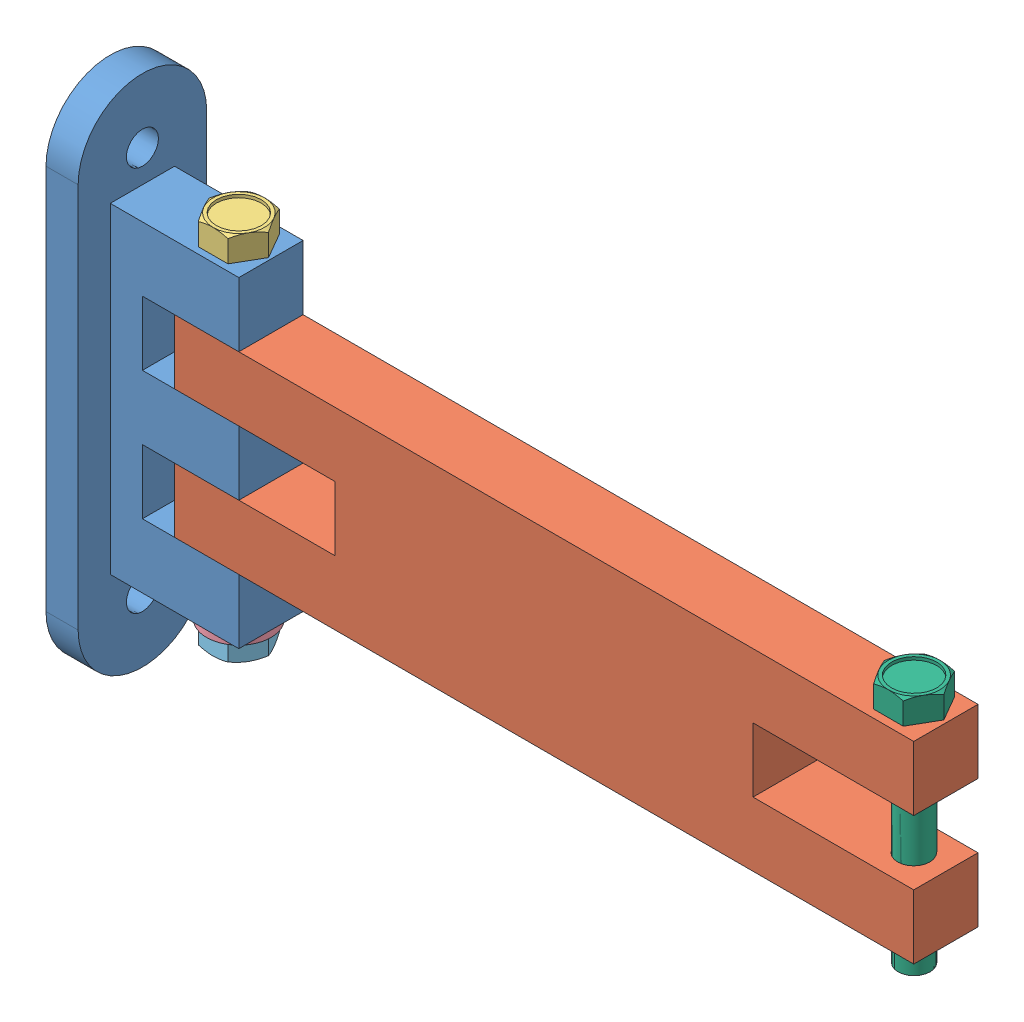
SolidWorks assembly TV Bracket, configuration Default. Lengths in mm.
Overall size (260 160 40).
6 component instances, 6 part files, 10 mates.
Components (placement in the parent):
- Wall Anchor-1: Wall Anchor [Default] at origin size (50 160 40)
- Link Arm-1: Link Arm [Default] at (135 0 0) size (230 60 20)
- M10 X 110 Bolt-1: M10 X 110 Bolt [B18.6.7M - M10 x 1.5 x 70 Indented HHMS --38N] at (30 57.5 0) x (0 -1 0) z (-0.866025 0 0.5) size (117.5 18.48 16)
- M10 Washer-1: M10 Washer [Default] at (30 -52 0) x (0 1 0) z (0 0 1) size (2 20 20)
- M10 Nut-1: M10 Nut [B18.2.4.1M - Hex nut, Style 1,  M10 x 1.5, with 16mm WAF --D-N] at (30 -52 0) x (0.866025 0 -0.5) z (0 1 0) size (16 18.48 6)
- M10 X 70 Bolt-1: M10 X 70 Bolt [B18.6.7M - M10 x 1.5 x 70 Indented HHMS --38N] at (239.7664 37.6092 -0.3551) x (0 -1 0) z (0 0 1) size (77.5 18.48 16)
Mates (geometry in assembly coordinates):
- Concentric1: concentric aligned: cylinder of Wall Anchor-1 through (30 -80 0) axis (0 1 0) radius 5; cylinder of Link Arm-1 through (30 -30 0) axis (0 1 0) radius 5
- Coincident1: coincident anti-aligned: plane of Wall Anchor-1 through (40 30 10) normal (0 -1 0); plane of Link Arm-1 through (250 30 10) normal (0 1 0)
- Concentric2: concentric aligned: cylinder of Wall Anchor-1 through (30 -80 0) axis (0 1 0) radius 5; cylinder of M10 X 110 Bolt-1 through (30 82.9 0) axis (0 1 0) radius 5
- Coincident2: coincident anti-aligned: plane of Wall Anchor-1 through (0 50 10) normal (0 1 0); plane of M10 X 110 Bolt-1 through (32.5 50 4.3301) normal (0 -1 0)
- Parallel1: parallel aligned: plane of Wall Anchor-1 through (0 50 10) normal (0 0 1); plane of M10 X 110 Bolt-1 through (25.3812 50 8) normal (0 0 1)
- Concentric3: concentric anti-aligned: cylinder of M10 X 110 Bolt-1 through (30 82.9 0) axis (0 1 0) radius 5; cylinder of M10 Washer-1 through (30 -50 0) axis (0 -1 0) radius 5
- Coincident4: coincident anti-aligned: plane of Wall Anchor-1 through (0 -50 10) normal (0 -1 0); plane of M10 Washer-1 through (30 -50 0) normal (0 1 0)
- Coincident5: coincident anti-aligned: plane of M10 Washer-1 through (30 -52 0) normal (0 -1 0); plane of M10 Nut-1 through (16.1436 -52 8) normal (0 1 0)
- Concentric4: concentric aligned: cylinder of M10 X 110 Bolt-1 through (30 82.9 0) axis (0 1 0) radius 5; cylinder of M10 Nut-1 through (30 -58 0) axis (0 1 0) radius 4.25
- Parallel2: parallel aligned: plane of Wall Anchor-1 through (0 50 10) normal (0 0 1); plane of M10 Nut-1 through (25.3812 -58 8) normal (0 0 1)
